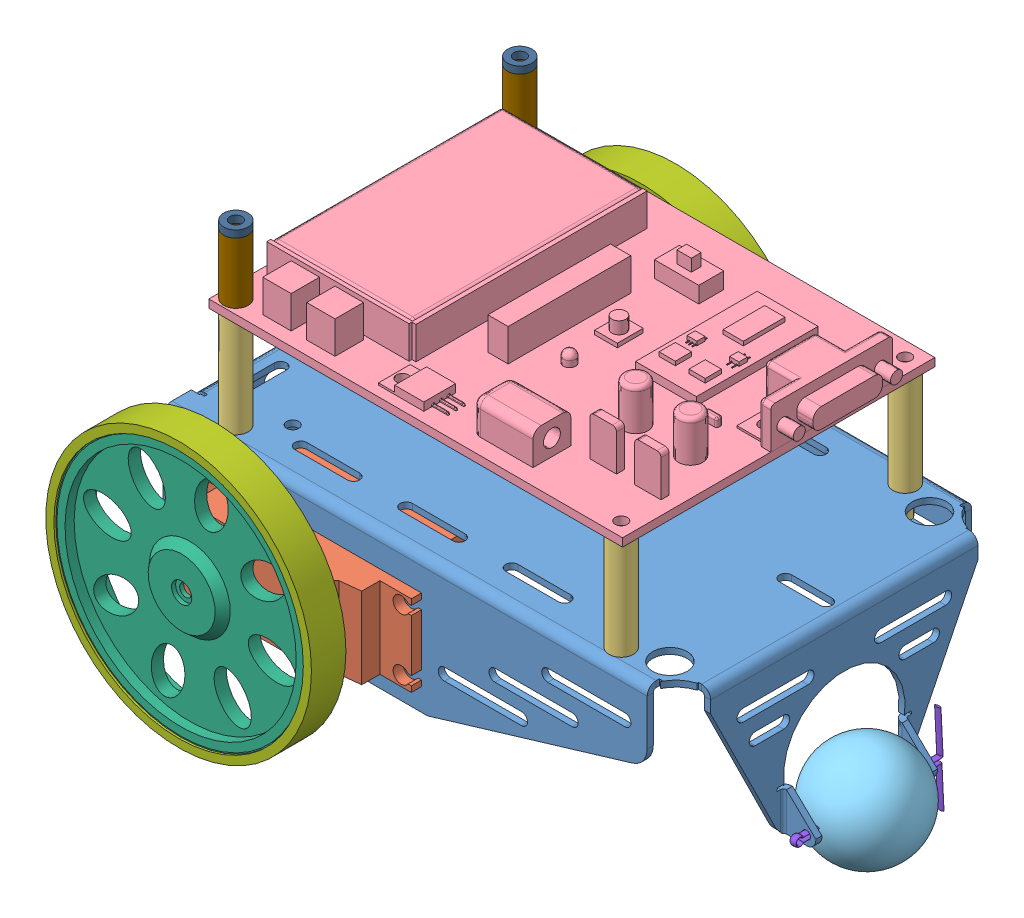
SolidWorks assembly boe-bot, configuration Default. Lengths in mm.
Overall size (165.23 101.44 120.5).
24 component instances, 15 part files, 44 mates.
Components (placement in the parent):
- boe-bot-1: boe-bot [Default] at (-57.0511 17.0738 35.706) size (135.98 39.5 80)
- servo motor-1: servo motor [Default] at (0.9489 -9.4262 -17.794) x (-1 0 0) z (0 0 -1) size (55.25 20 44)
- servo motor-2: servo motor [Default] at (-1.0511 10.5738 9.206) x (-1 0 0) z (0 0 1) size (55.25 20 44)
- odstojnik 25mm-1: odstojnik 25mm [Default] at (-44.0511 18.5738 -39.294) size (6 32 6)
- odstojnik 25mm-2: odstojnik 25mm [Default] at (50.9489 18.5738 -39.294) size (6 32 6)
- odstojnik 25mm-3: odstojnik 25mm [Default] at (-44.0511 18.5738 30.706) size (6 32 6)
- odstojnik 25mm-4: odstojnik 25mm [Default] at (50.9489 18.5738 30.706) size (6 32 6)
- parallax ploćica-1: parallax ploćica [Default] at (54.7095 43.5738 34.1476) x (0 0 -1) z (1 0 0) size (77 12 106.02)
- caster-1: caster [Default] at (76.6155 -18.6272 -4.1291) x (0.940928 -0.338607 0) z (-0.338607 -0.940928 0) size (25 24.97 25)
- felga-2: felga [Default] at (-32.9316 0.5738 51.706) x (-0.967221 0.253934 0) z (0 0 1) size (65 65 9.25)
- felga-3: felga [Default] at (-30.9316 0.5738 -60.294) x (-0.999649 0.026483 0) z (0 0 -1) size (65 65 9.25)
- guma-2: guma [Default] at (-32.9316 33.3238 55.956) size (65.5 65.5 8.5)
- guma-3: guma [Default] at (-30.9316 33.3238 -56.044) size (65.5 65.5 8.5)
- kopča-1: kopča [Default] at (76.8069 -19.1051 -21.7203) x (0.003801 0.00007 -0.999993) z (0.998716 0.050516 0.003799) size (37.08 21.39 1.55)
- odstojnik 15 mm-1: odstojnik 15 mm [Default] at (-44.0511 45.5738 -39.294) size (6 15 6)
- odstojnik 1,75 mm-1: odstojnik 1,75 mm [Default] at (-44.0511 60.5738 -39.294) size (6 1.75 6)
- odstojnik 15 mm-2: odstojnik 15 mm [Default] at (-44.0511 45.5738 30.706) size (6 15 6)
- odstojnik 1,75 mm-2: odstojnik 1,75 mm [Default] at (-44.0511 60.5738 30.706) size (6 1.75 6)
- nosač motora-1: nosač motora [Default] at (-79.4507 70.8238 -50.1039) x (0.011833 0 0.99993) z (-0.99993 0 0.011833) size (24.5 16.5 32) (hidden)
- pico servo motor-1: pico servo motor [Default] at (-69.3216 41.8238 -44.794) size (32 29 11) (hidden)
- pico servo motor-2: pico servo motor [Default] at (-74.6537 85.3238 -46.1604) x (0.99993 0 -0.011833) z (0 -1 0) size (32 29 11) (hidden)
- nosač kamere-1: nosač kamere [Default] at (47.0444 60.5738 -46.8668) x (0 0 1) z (-1 0 0) size (83 1.5 8) (hidden)
- zvijezda-1: zvijezda [Default] at (-68.2991 79.8238 -16.2335) x (0.795831 -0.605445 -0.009418) z (0.605403 0.795887 -0.007164) size (33.94 4.2 24.75) (hidden)
- koplje-1: koplje [Default] at (-41.5546 60.3928 -13.5497) x (0.194321 0.238146 -0.951591) z (0.623933 0.718549 0.307236) size (6 250 6) (hidden)
Mates (geometry in assembly coordinates):
- Coincident1: coincident anti-aligned: plane of boe-bot-1 through (-41.0511 10.5738 82.706) normal (0 -1 0); plane of servo motor-1 through (0.9489 10.5738 -53.794) normal (0 1 0)
- Coincident2: coincident anti-aligned: plane of boe-bot-1 through (0.9489 10.5738 82.706) normal (-1 0 0); plane of servo motor-1 through (0.9489 -9.4262 -53.794) normal (1 0 0)
- Coincident3: coincident anti-aligned: plane of boe-bot-1 through (62.3419 17.0738 -44.294) normal (0 0 -1); plane of servo motor-1 through (-46.5511 10.5738 -44.294) normal (0 0 1)
- Coincident5: coincident anti-aligned: plane of boe-bot-1 through (-41.0511 10.5738 82.706) normal (0 -1 0); plane of servo motor-2 through (-1.0511 10.5738 45.206) normal (0 1 0)
- Coincident7: coincident anti-aligned: plane of boe-bot-1 through (-41.0511 10.5738 82.706) normal (1 0 0); plane of servo motor-2 through (-41.0511 10.5738 45.206) normal (-1 0 0)
- Coincident8: coincident anti-aligned: plane of boe-bot-1 through (-57.0511 17.0738 35.706) normal (0 0 1); plane of servo motor-2 through (-48.5511 -9.4262 35.706) normal (0 0 -1)
- Coincident9: coincident anti-aligned: circle of boe-bot-1; cylinder of odstojnik 25mm-1 through (-44.0511 11.5738 -39.294) axis (0 1 0) radius 1.5
- Coincident10: coincident anti-aligned: plane of boe-bot-1 through (70.2876 18.5738 -45.2244) normal (0 1 0); plane of odstojnik 25mm-1 through (-44.0511 18.5738 -39.294) normal (0 -1 0)
- Concentric1: concentric aligned: cylinder of boe-bot-1 through (50.9489 3.5738 -39.294) axis (0 1 0) radius 1.5; cylinder of odstojnik 25mm-2 through (50.9489 11.5738 -39.294) axis (0 1 0) radius 1.5
- Coincident11: coincident anti-aligned: plane of boe-bot-1 through (70.2876 18.5738 -45.2244) normal (0 1 0); plane of odstojnik 25mm-2 through (50.9489 18.5738 -39.294) normal (0 -1 0)
- Coincident12: coincident anti-aligned: cylinder of odstojnik 25mm-4 through (50.9489 11.5738 30.706) axis (0 1 0) radius 1.5; circle of boe-bot-1
- Coincident13: coincident anti-aligned: plane of boe-bot-1 through (70.2876 18.5738 -45.2244) normal (0 1 0); plane of odstojnik 25mm-4 through (50.9489 18.5738 30.706) normal (0 -1 0)
- Coincident14: coincident anti-aligned: circle of boe-bot-1; cylinder of odstojnik 25mm-3 through (-44.0511 11.5738 30.706) axis (0 1 0) radius 1.5
- Coincident15: coincident anti-aligned: plane of boe-bot-1 through (70.2876 18.5738 -45.2244) normal (0 1 0); plane of odstojnik 25mm-3 through (-44.0511 18.5738 30.706) normal (0 -1 0)
- Concentric3: concentric anti-aligned: circle of boe-bot-1; circle of caster-1
- Concentric4: concentric aligned: cylinder of servo motor-2 through (-32.9316 0.5738 53.206) axis (0 0 -1) radius 3; cylinder of felga-2 through (-32.9316 0.5738 53.206) axis (0 0 -1) radius 2.75
- Coincident18: coincident anti-aligned: plane of servo motor-2 through (-32.9316 0.5738 53.206) normal (0 0 1); plane of felga-2 through (-32.9316 0.5738 53.206) normal (0 0 -1)
- Concentric5: concentric aligned: cylinder of servo motor-1 through (-30.9316 0.5738 -61.794) axis (0 0 1) radius 3; cylinder of felga-3 through (-30.9316 0.5738 -61.794) axis (0 0 1) radius 2.75
- Coincident19: coincident anti-aligned: plane of servo motor-1 through (-30.9316 0.5738 -61.794) normal (0 0 -1); plane of felga-3 through (-30.9316 0.5738 -61.794) normal (0 0 1)
- Concentric7: concentric aligned: cylinder of felga-2 through (-32.9316 0.5738 72.8944) axis (0 0 1) radius 32.5; cylinder of guma-2 through (-32.9316 0.5738 71.4243) axis (0 0 1) radius 31.95
- Coincident20: coincident anti-aligned: circle of felga-2; plane of guma-2 through (-32.9316 31.3238 55.456) normal (0 0 -1)
- Concentric8: concentric anti-aligned: cylinder of felga-3 through (-30.9316 0.5738 -81.4824) axis (0 0 -1) radius 32.5; cylinder of guma-3 through (-30.9316 0.5738 -40.5757) axis (0 0 1) radius 31.95
- Coincident21: coincident aligned: circle of felga-3; plane of guma-3 through (-30.9316 31.3238 -56.544) normal (0 0 -1)
- Concentric9: concentric anti-aligned: circle of boe-bot-1; circle of caster-1
- Concentric11: concentric aligned: circle of parallax ploćica-1; circle of odstojnik 15 mm-1
- Coincident23: coincident anti-aligned: plane of parallax ploćica-1 through (-47.2905 45.5738 34.1476) normal (0 1 0); plane of odstojnik 15 mm-1 through (-44.0511 45.5738 -39.294) normal (0 -1 0)
- Coincident24: coincident aligned: circle of odstojnik 15 mm-1; circle of odstojnik 1,75 mm-1
- Concentric12: concentric aligned: circle of odstojnik 25mm-1; circle of parallax ploćica-1
- Coincident26: coincident anti-aligned: plane of odstojnik 25mm-1 through (-44.0511 43.5738 -39.294) normal (0 1 0); plane of parallax ploćica-1 through (-47.2905 43.5738 34.1476) normal (0 -1 0)
- Coincident27: coincident aligned: circle of odstojnik 25mm-4; circle of parallax ploćica-1
- Coincident29: coincident aligned: circle of parallax ploćica-1; circle of odstojnik 15 mm-2
- Coincident30: coincident aligned: circle of odstojnik 15 mm-2; circle of odstojnik 1,75 mm-2
- Concentric13: concentric aligned: cylinder of odstojnik 1,75 mm-1 through (-44.0511 60.5738 -39.294) axis (0 1 0) radius 1.5; cylinder of pico servo motor-1 through (-44.0511 53.8238 -39.294) axis (0 1 0) radius 2
- Coincident40: coincident anti-aligned: plane of odstojnik 1,75 mm-1 through (-44.0511 62.3238 -39.294) normal (0 1 0); plane of pico servo motor-1 through (-58.8212 62.3238 -33.794) normal (0 -1 0)
- Concentric14: concentric aligned: cylinder of nosač motora-1 through (-63.3216 70.8238 -39.294) axis (0 1 0) radius 1.25; cylinder of pico servo motor-1 through (-63.3216 67.8238 -39.294) axis (0 1 0) radius 1.5
- Coincident41: coincident anti-aligned: plane of nosač motora-1 through (-47.4529 70.8238 -50.4825) normal (0 -1 0); plane of pico servo motor-1 through (-63.3216 70.8238 -39.294) normal (0 1 0)
- Coincident42: coincident anti-aligned: plane of nosač motora-1 through (-74.701 85.3238 -50.1601) normal (0 -1 0); plane of pico servo motor-2 through (-64.3527 85.3238 -63.076) normal (0 1 0)
- Coincident43: coincident anti-aligned: plane of nosač motora-1 through (-74.701 85.3238 -50.1601) normal (0.99993 0 -0.011833); plane of pico servo motor-2 through (-74.8524 74.3238 -62.9517) normal (-0.99993 0 0.011833)
- Coincident44: coincident anti-aligned: plane of nosač motora-1 through (-47.163 72.3238 -25.9842) normal (0.011833 0 0.99993); plane of pico servo motor-2
- Parallel1: parallel anti-aligned: line of boe-bot-1 through (68.7123 18.5738 28.6638) axis (0 0 -1); line of nosač kamere-1 through (55.0444 62.0738 -41.8668) axis (0 0 1)
- Concentric15: concentric aligned: cylinder of zvijezda-1 through (-68.3109 79.8238 -17.2334) axis (-0.011833 0 -0.99993) radius 2; cylinder of pico servo motor-2 through (-68.3109 79.8238 -17.2334) axis (-0.011833 0 -0.99993) radius 2.5
- Coincident46: coincident anti-aligned: plane of pico servo motor-2; plane of zvijezda-1 through (-68.3109 79.8238 -17.2334) normal (-0.011833 0 -0.99993)
- Tangent2: tangent anti-aligned: plane of zvijezda-1 through (-77.8514 87.0861 -16.1204) normal (0.011833 0 0.99993); cylinder of koplje-1 through (-243.8961 235.0668 -11.1552) axis (-0.756932 0.653432 0.008958) radius 3
- Coincident47: coincident: line of zvijezda-1 through (-65.1175 80.7031 -16.2711) axis (0.756932 -0.653432 -0.008958); cylinder of koplje-1 through (-243.8961 235.0668 -11.1552) axis (-0.756932 0.653432 0.008958) radius 3
